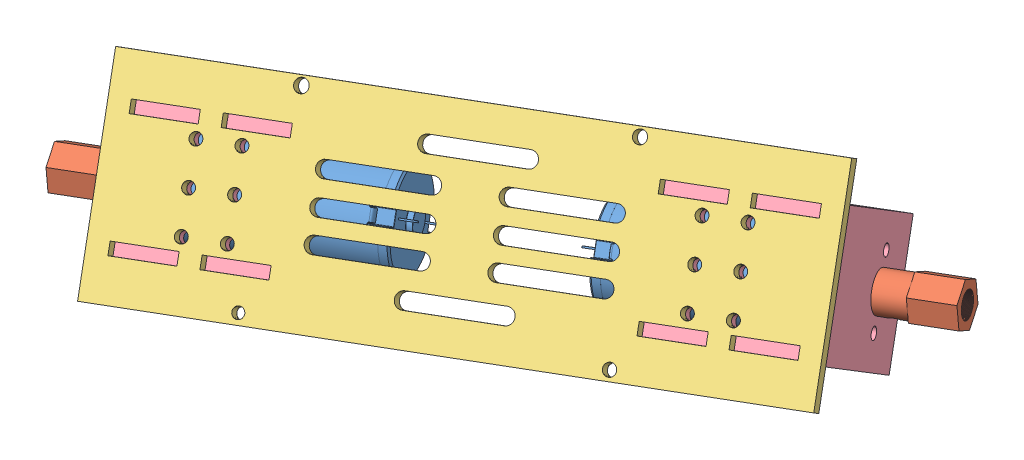
SolidWorks assembly MotorHolder, configuration Default. Lengths in mm.
Overall size (187.24 71.29 118.07).
7 component instances, 4 part files, 8 mates.
Components (placement in the parent):
- JGA25-370 12V Planetary Geared Motor-1: JGA25-370 12V Planetary Geared Motor [Ratio 171 & 226] at (24.1989 15.1159 25.3332) x (0.282692 0.578568 0.765078) z (-0.295603 0.811339 -0.504329) size (25.02 71.1 25)
- Coupler-1: Coupler [Default] at (30.1303 15.6592 22.7307) x (0.275788 -0.848644 0.45138) z (0.302054 0.522318 0.797463) size (10.5 19 12.12)
- Base Plate-1: Base Plate [Default] at (-38.6065 24.8376 77.7853) x (0.912526 0.083589 -0.400386) z (-0.295603 0.811339 -0.504329) size (160 3 52)
- Motor holder-1: Motor holder [Default] at (37.686 18.4303 50.5198) x (-0.295603 0.811339 -0.504329) z (-0.912526 -0.083589 0.400386) size (33 37.5 40)
- Motor holder-2: Motor holder [Default] at (-116.5951 27.7735 100.4603) x (0.295603 -0.811339 0.504329) z (0.912526 0.083589 -0.400386) size (33 37.5 40)
- Coupler-2: Coupler [Default] at (-123.1741 1.6162 89.9955) x (0.275788 -0.848644 0.45138) z (-0.302054 -0.522318 -0.797463) size (10.5 19 12.12)
- JGA25-370 12V Planetary Geared Motor-2: JGA25-370 12V Planetary Geared Motor [Ratio 171 & 226] at (-117.2427 2.1595 87.393) x (-0.282692 -0.578568 -0.765078) z (-0.295603 0.811339 -0.504329) size (25.02 71.1 25)
Mates (geometry in assembly coordinates):
- Concentric2: concentric aligned: circle of JGA25-370 12V Planetary Geared Motor-1; circle of Motor holder-1
- Concentric3: concentric aligned: cylinder of JGA25-370 12V Planetary Geared Motor-1 through (21.6863 22.0123 21.0464) axis (0.912526 0.083589 -0.400386) radius 1.25; cylinder of Motor holder-1 through (23.9676 22.2213 20.0454) axis (0.912526 0.083589 -0.400386) radius 1.5
- Coincident5: coincident anti-aligned: plane of JGA25-370 12V Planetary Geared Motor-1 through (24.1989 15.1159 25.3332) normal (0.912526 0.083589 -0.400386); plane of Motor holder-1 through (16.5268 19.2425 8.7091) normal (-0.912526 -0.083589 0.400386)
- Concentric5: concentric anti-aligned: circle of JGA25-370 12V Planetary Geared Motor-1; circle of Coupler-1
- Coincident7: coincident anti-aligned: plane of Coupler-1 through (26.4802 15.3249 24.3322) normal (-0.912526 -0.083589 0.400386); plane of Motor holder-1 through (29.4091 41.1478 36.3986) normal (0.912526 0.083589 -0.400386)
- Coincident9: coincident anti-aligned: plane of Base Plate-1 through (-39.4546 23.1019 75.49) normal (-0.282692 -0.578568 -0.765078); plane of Motor holder-1 through (37.686 18.4303 50.5198) normal (0.282692 0.578568 0.765078)
- Coincident10: coincident: moEndPointRef_w of Base Plate-1; moEndPointRef_w of Motor holder-1
- Coincident11: coincident anti-aligned: line of Base Plate-1 through (25.8618 50.8839 30.3466) axis (0.295603 -0.811339 0.504329); line of Motor holder-1 through (38.425 16.402 51.7806) axis (-0.295603 0.811339 -0.504329)
